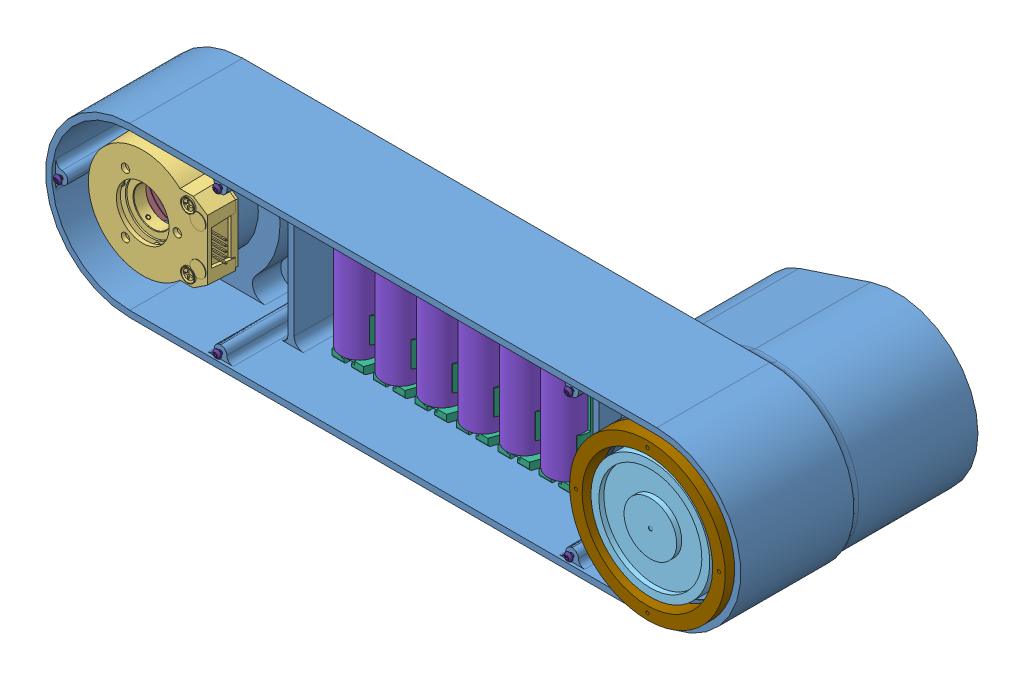
SolidWorks assembly Wall Link, configuration Default. Lengths in mm.
Overall size (351.79 85.09 127.22).
66 component instances, 23 part files, 117 mates.
Components (placement in the parent):
- Wall Link Frame-1: Wall Link Frame [Default] at (-125.008 20.7132 -31.1742) size (351.79 85.09 121.22)
- ring_gear-1: ring_gear [Default] at (-125.008 20.7132 -35.0242) x (0 0 -1) z (1 0 0) size (5 75 75)
- Magnet Encoders E3-X-750-X-H-D-X-1: Magnet Encoders E3-X-750-X-H-D-X [Default] at (141.692 20.7132 -54.2232) x (0 1 0) z (-1 0 0) size (55.98 16.26 66.52)
- magnet holder-1: magnet holder [Default] at (145.4704 22.0262 -2.1382) x (0.944598 0.32823 0) z (-0.32823 0.944598 0) size (50.8 63.9 50.6)
- EM237 Magnet-1: EM237 Magnet [Default] at (141.692 20.7132 10.3713) x (-0.997847 -0.065578 0) z (-0.065578 0.997847 0) size (60.08 25.02 60.08)
- PCB_Battery Assembly-3: PCB_Battery Assembly [Default] at (93.7956 -0.9181 88.7233) x (1 0 0) z (0 1 0) size (138.43 24.87 77.22)
  - Battery Holder - keystone-PN1043-1: Battery Holder - keystone-PN1043 [Default] at (-125.3925 103.3982 18.9155) x (1 0 0) z (0 0 -1) size (20.65 18.93 77.14)
  - Battery PCB-1: Battery PCB [Default] at (-148.3186 115.135 -16.9005) x (1 0 0) z (0 -1 0) size (138.43 77.06 1.59)
  - battery_6612-1: battery_6612 [Default] at (-117.0385 104.4035 -11.3639) x (-0.413992 0.91028 0) z (0.91028 0.413992 0) size (18.3 65.05 18.3)
  - battery_6612-2: battery_6612 [Default] at (-137.9935 104.4035 54.6265) x (-0.916106 0.400937 0) z (-0.400937 -0.916106 0) size (18.3 65.05 18.3)
  - Battery Holder - keystone-PN1043-2: Battery Holder - keystone-PN1043 [Default] at (-129.6396 103.3982 24.3471) x (-1 0 0) z (0 0 1) size (20.65 18.93 77.14)
  - Battery Holder - keystone-PN1043-3: Battery Holder - keystone-PN1043 [Default] at (-104.4375 103.3982 18.9155) x (1 0 0) z (0 0 -1) size (20.65 18.93 77.14)
  - battery_6612-3: battery_6612 [Default] at (-96.0835 104.4035 -10.3735) x (1 0 0) z (0 -1 0) size (18.3 65.05 18.3)
  - Battery Holder - keystone-PN1043-4: Battery Holder - keystone-PN1043 [Default] at (-83.4825 103.3982 18.9155) x (1 0 0) z (0 0 -1) size (20.65 18.93 77.14)
  - Battery Holder - keystone-PN1043-5: Battery Holder - keystone-PN1043 [Default] at (-45.8196 103.3982 24.3471) x (-1 0 0) z (0 0 1) size (20.65 18.93 77.14)
  - Battery Holder - keystone-PN1043-6: Battery Holder - keystone-PN1043 [Default] at (-41.5725 103.3982 18.9155) x (1 0 0) z (0 0 -1) size (20.65 18.93 77.14)
  - battery_6612-4: battery_6612 [Default] at (-75.1285 104.4035 -11.3639) x (-0.923728 -0.383049 0) z (-0.383049 0.923728 0) size (18.3 65.05 18.3)
  - battery_6612-5: battery_6612 [Default] at (-54.1735 104.4035 54.6265) x (-1 0 0) z (0 -1 0) size (18.3 65.05 18.3)
  - battery_6612-6: battery_6612 [Default] at (-33.2185 104.4035 -11.3639) x (-0.923728 -0.383049 0) z (-0.383049 0.923728 0) size (18.3 65.05 18.3)
- Delrin_Ring-1: Delrin_Ring [Default] at (141.692 20.7132 24.3883) x (1 0 0) z (0 1 0) size (78.74 9.53 78.74)
- Neoprene Ring-1: Neoprene Ring [Default] at (141.692 20.7132 14.8633) x (0 1 0) z (-1 0 0) size (78.74 3.17 78.74)
- Slip Ring M322M1-0600-1: Slip Ring M322M1-0600 [Default] at (141.692 20.7132 -74.8152) x (0.866025 0.5 0) z (0 0 1) size (44 44 48)
- Wall Link Acrylic Cover-1: Wall Link Acrylic Cover [Default] at (141.692 20.7132 18.0383) x (-1 0 0) z (0 1 0) size (280.8 1.59 78.74) (hidden)
- Magnet Encoders E3-X-750-X-H-D-X-2: Magnet Encoders E3-X-750-X-H-D-X [Default] at (-125.008 20.7132 0.8148) x (0 1 0) z (1 0 0) size (55.98 16.26 66.52)
- Acrylic Cover 2 Wall Link-1: Acrylic Cover 2 Wall Link [Default] at (141.692 20.7132 -101.5942) x (-1 0 0) z (0 0 1) size (103.7 76.2 1.59)
- Bearing - .750-1: Bearing - .750 [3760T241] at (-125.008 20.7132 -11.3454) x (-0.923728 -0.383049 0) z (0 0 -1) size (41.27 41.27 11.11)
- Bearing - .750-3: Bearing - .750 [3760T241] at (141.692 20.7132 -27.7755) size (41.27 41.27 11.11)
- Bearing - .750-2: Bearing - .750 [3760T241] at (141.692 20.7132 -38.888) x (0.923728 0.383049 0) z (0 0 -1) size (41.27 41.27 11.11)
- 1.625 Bore Internal Retaining Ring-1: 1.625 Bore Internal Retaining Ring [99142A560] at (-125.008 20.7132 -5.7892) x (-0.62577 0.780008 0) z (-0.780008 -0.62577 0) size (45.82 1.57 43.68)
- .75 Bore External Retaining Ring-1: .75 Bore External Retaining Ring [97633A250] at (141.692 21.2592 -44.9776) x (0 0 -1) z (1 0 0) size (1.07 23.39 21.18)
- 1.625 Bore Internal Retaining Ring-2: 1.625 Bore Internal Retaining Ring [99142A560] at (141.692 20.7132 -20.6444) x (1 0 0) z (0 -1 0) size (45.82 1.57 43.68)
- Dowel Pin - .0625-1: Dowel Pin - .0625 [97395A414] at (141.692 -15.4818 8.5133) x (0 0 1) z (0.923728 0.383049 0) size (19.05 1.59 1.59)
- Dowel Pin - .0625-2: Dowel Pin - .0625 [97395A414] at (141.692 56.9082 8.5133) x (0 0 1) z (0.923728 0.383049 0) size (19.05 1.59 1.59)
- Dowel Pin - .0625-3: Dowel Pin - .0625 [97395A414] at (177.887 20.7132 8.5133) x (0 0 1) z (0.923728 0.383049 0) size (19.05 1.59 1.59)
- Dowel Pin - .0625-4: Dowel Pin - .0625 [97395A414] at (105.497 20.7132 8.5133) x (0 0 1) z (0.923728 0.383049 0) size (19.05 1.59 1.59)
- 2-56 Screw-1: 2-56 Screw [98164A427] at (97.242 -15.4818 20.7942) size (4.17 4.17 10.95)
- 2-56 Screw-2: 2-56 Screw [98164A427] at (97.242 56.9082 20.7942) size (4.17 4.17 10.95)
- 2-56 Screw-3: 2-56 Screw [98164A427] at (-80.558 56.9082 20.7942) size (4.17 4.17 10.95)
- 2-56 Screw-4: 2-56 Screw [98164A427] at (-161.203 20.7132 20.7942) size (4.17 4.17 10.95)
- 2-56 Screw-5: 2-56 Screw [98164A427] at (-80.558 -15.4818 20.7942) size (4.17 4.17 10.95)
- M5 Screws-1: M5 Screws [91352A131] at (150.442 35.8687 -77.5652) x (-0.923728 -0.383049 0) z (0 0 -1) size (9.5 9.5 13.21)
- M5 Screws-2: M5 Screws [91352A131] at (150.442 5.5578 -77.5652) x (0.923728 0.383049 0) z (0 0 -1) size (9.5 9.5 13.21)
- M5 Screws-3: M5 Screws [91352A131] at (124.192 20.7132 -77.5652) x (-0.923728 -0.383049 0) z (0 0 -1) size (9.5 9.5 13.21)
- M5 Nylon Spacer-1: M5 Nylon Spacer [93657A042] at (150.442 35.8687 -69.4152) size (8 8 6)
- M5 Nylon Spacer-2: M5 Nylon Spacer [93657A042] at (124.192 20.7132 -69.4152) size (8 8 6)
- M5 Nylon Spacer-3: M5 Nylon Spacer [93657A042] at (150.442 5.5578 -69.4152) size (8 8 6)
- 4-40 Screws-1: 4-40 Screws [92949A108] at (-125.008 43.7256 2.3134) size (5.41 5.41 11.35)
- 4-40 Screws-2: 4-40 Screws [92949A108] at (141.692 -2.2992 -55.7218) x (0.923728 0.383049 0) z (0 0 -1) size (5.41 5.41 11.35)
- 4-40 Screws-3: 4-40 Screws [92949A108] at (141.692 43.7256 -55.7218) x (0.923728 0.383049 0) z (0 0 -1) size (5.41 5.41 11.35)
- 4-40 Screws-4: 4-40 Screws [92949A108] at (-125.008 -2.2992 2.3134) x (0.999053 -0.043504 0) z (0 0 1) size (5.41 5.41 11.35)
- 2-56 Screw-6: 2-56 Screw [98164A427] at (79.2674 20.7132 -102.7626) x (-0.923728 -0.383049 0) z (0 0 -1) size (4.17 4.17 10.95)
- 2-56 Screw-7: 2-56 Screw [98164A427] at (176.617 20.7132 -102.7626) x (-0.923728 -0.383049 0) z (0 0 -1) size (4.17 4.17 10.95)
- 2-56 Screw-8: 2-56 Screw [98164A427] at (116.292 49.0821 -102.7626) x (-0.923728 -0.383049 0) z (0 0 -1) size (4.17 4.17 10.95)
- 2-56 Screw-9: 2-56 Screw [98164A427] at (116.292 -7.6556 -102.7626) x (-0.923728 -0.383049 0) z (0 0 -1) size (4.17 4.17 10.95)
- 2-56 Screw-10: 2-56 Screw [98164A427] at (74.382 52.895 -23.6558) size (4.17 4.17 10.95)
- 2-56 Screw-12: 2-56 Screw [98164A427] at (74.382 -11.4686 -23.6558) size (4.17 4.17 10.95)
- 2-56 Screw-13: 2-56 Screw [98164A427] at (-57.698 52.895 -23.6558) size (4.17 4.17 10.95)
- 2-56 Screw-14: 2-56 Screw [98164A427] at (-57.698 -11.4686 -23.6558) size (4.17 4.17 10.95)
- #2 Spacer-1: #2 Spacer [94639A188] at (74.382 52.895 -28.793) x (0.8148 0.579742 0) z (0 0 1) size (6.35 6.35 4.76)
- #2 Spacer-2: #2 Spacer [94639A188] at (74.382 -11.4686 -28.793) x (0.211674 0.97734 0) z (0 0 1) size (6.35 6.35 4.76)
- #2 Spacer-3: #2 Spacer [94639A188] at (-57.698 52.895 -28.793) x (0.886571 -0.462592 0) z (0 0 1) size (6.35 6.35 4.76)
- #2 Spacer-4: #2 Spacer [94639A188] at (-57.698 -11.4686 -28.793) x (-0.923728 -0.383049 0) z (0 0 -1) size (6.35 6.35 4.76)
- 8-32 Low Profile Screws-1: 8-32 Low Profile Screws [92220A153] at (-125.008 -13.5768 -31.1742) x (0 0 1) z (-1 0 0) size (15.09 6.86 6.86)
- 8-32 Low Profile Screws-2: 8-32 Low Profile Screws [92220A153] at (-90.718 20.7132 -31.1742) x (0 0 1) z (-1 0 0) size (15.09 6.86 6.86)
- 8-32 Low Profile Screws-3: 8-32 Low Profile Screws [92220A153] at (-125.008 55.0032 -31.1742) x (0 0 1) z (-0.52487 0.851182 0) size (15.09 6.86 6.86)
- 8-32 Low Profile Screws-4: 8-32 Low Profile Screws [92220A153] at (-159.298 20.7132 -31.1742) x (0 0 1) z (-1 0 0) size (15.09 6.86 6.86)
Mates (geometry in assembly coordinates):
- Coincident1: coincident aligned: plane of Wall Link Frame-1 through (-125.008 20.7132 -37.5242) normal (0 0 -1); plane of ring_gear-1 through (-125.008 20.7132 -37.5242) normal (0 0 -1)
- Coincident2: coincident aligned: line of Wall Link Frame-1 through (-125.008 20.7132 -32.4442) axis (0 0 -1); line of ring_gear-1 through (-125.008 20.7132 -32.5242) axis (0 0 -1)
- Concentric1: concentric anti-aligned: cylinder of Magnet Encoders E3-X-750-X-H-D-X-1 through (141.692 20.7132 -60.7764) axis (0 0 -1) radius 9.5263; line of Wall Link Frame-1 through (141.692 20.7132 -50.7942) axis (0 0 1)
- Coincident4: coincident anti-aligned: plane of Wall Link Frame-1 through (-125.008 20.7132 -50.7942) normal (0 0 -1); plane of Magnet Encoders E3-X-750-X-H-D-X-1 through (141.692 20.7132 -50.7942) normal (0 0 1)
- Perpendicular1: perpendicular: line of Wall Link Frame-1 through (141.692 20.7132 -31.1742) axis (-1 0 0); line of Magnet Encoders E3-X-750-X-H-D-X-1 through (108.9495 36.0106 -66.4152) axis (0 -1 0)
- Coincident7: coincident aligned: line of Wall Link Frame-1 through (141.692 20.7132 -50.7942) axis (0 0 1); line of magnet holder-1 through (141.692 20.7132 -66.0342) axis (0 0 1)
- Coincident8: coincident aligned: plane of magnet holder-1; plane of EM237 Magnet-1 through (141.692 20.7132 -2.1382) normal (0 0 -1)
- Concentric2: concentric anti-aligned: line of Wall Link Frame-1 through (141.692 20.7132 -50.7942) axis (0 0 1); cylinder of EM237 Magnet-1 through (141.692 20.7132 22.8808) axis (0 0 -1) radius 30.0419
- Coincident12: coincident anti-aligned: plane of Wall Link Frame-1 through (-125.008 20.7132 -16.9017) normal (0 0 1); plane of Bearing - .750-1 through (-132.7004 39.2634 -16.9017) normal (0 0 -1)
- Coincident13: coincident anti-aligned: line of Wall Link Frame-1 through (-125.008 20.7132 -32.4442) axis (0 0 -1); line of Bearing - .750-1 through (-125.008 20.7132 -16.9017) axis (0 0 1)
- Coincident15: coincident anti-aligned: plane of Wall Link Frame-1 through (-125.008 20.7132 -5.7892) normal (0 0 1); plane of 1.625 Bore Internal Retaining Ring-1 through (-144.945 18.8067 -5.7892) normal (0 0 -1)
- Concentric3: concentric aligned: cylinder of Wall Link Frame-1 through (-125.008 20.7132 -4.062) axis (0 0 -1) radius 21.59; cylinder of 1.625 Bore Internal Retaining Ring-1 through (-125.008 20.7132 -4.2144) axis (0 0 -1) radius 22.9108
- Concentric4: concentric anti-aligned: line of Wall Link Frame-1 through (-125.008 20.7132 -32.4442) axis (0 0 -1); cylinder of Magnet Encoders E3-X-750-X-H-D-X-2 through (-125.008 20.7132 7.368) axis (0 0 1) radius 9.5263
- Coincident18: coincident anti-aligned: plane of Wall Link Frame-1 through (-125.008 20.7132 -2.6142) normal (0 0 1); plane of Magnet Encoders E3-X-750-X-H-D-X-2 through (-125.008 20.7132 -2.6142) normal (0 0 -1)
- Parallel1: parallel: line of Wall Link Frame-1 through (141.692 20.7132 -31.1742) axis (-1 0 0); plane of Magnet Encoders E3-X-750-X-H-D-X-2 through (-99.2764 41.2364 -0.76) normal (0 0.999391 0.034899)
- Concentric5: concentric aligned: line of Wall Link Frame-1 through (141.692 20.7132 19.6258) axis (0 0 -1); cylinder of Bearing - .750-2 through (141.692 20.7132 -44.4442) axis (0 0 -1) radius 20.6375
- Coincident20: coincident anti-aligned: plane of Wall Link Frame-1 through (141.692 20.7132 -44.4442) normal (0 0 1); plane of Bearing - .750-2 through (149.3843 2.1631 -44.4442) normal (0 0 -1)
- Concentric6: concentric anti-aligned: cylinder of Bearing - .750-3 through (141.692 20.7132 -22.2192) axis (0 0 1) radius 20.6375; line of Wall Link Frame-1 through (141.692 20.7132 19.6258) axis (0 0 -1)
- Coincident21: coincident anti-aligned: plane of Bearing - .750-2 through (149.3843 2.1631 -33.3317) normal (0 0 1); plane of Bearing - .750-3 through (141.692 40.7951 -33.3317) normal (0 0 -1)
- Coincident22: coincident anti-aligned: plane of Wall Link Frame-1 through (141.692 20.7132 -22.2192) normal (0 0 1); plane of 1.625 Bore Internal Retaining Ring-2 through (152.6808 3.9692 -22.2192) normal (0 0 -1)
- Concentric7: concentric anti-aligned: line of Wall Link Frame-1 through (141.692 20.7132 19.6258) axis (0 0 -1); cylinder of 1.625 Bore Internal Retaining Ring-2 through (141.692 20.7132 -22.2192) axis (0 0 1) radius 22.9108
- Coincident24: coincident anti-aligned: plane of magnet holder-1 through (153.6884 24.8818 -22.2192) normal (0 0 -1); plane of Bearing - .750-3 through (141.692 34.4687 -22.2192) normal (0 0 1)
- Coincident25: coincident anti-aligned: plane of magnet holder-1 through (141.692 20.7132 -44.4442) normal (0 0 -1); plane of .75 Bore External Retaining Ring-1 through (141.692 21.2592 -44.4442) normal (0 0 1)
- Concentric8: concentric anti-aligned: line of Wall Link Frame-1 through (141.692 20.7132 19.6258) axis (0 0 -1); cylinder of .75 Bore External Retaining Ring-1 through (141.692 20.7132 -45.511) axis (0 0 1) radius 10.592
- Concentric10: concentric anti-aligned: line of Wall Link Frame-1 through (141.692 20.7132 19.6258) axis (0 0 -1); cylinder of Neoprene Ring-1 through (141.692 20.7132 11.6883) axis (0 0 1) radius 33.02
- Concentric9: concentric aligned: cylinder of Wall Link Frame-1 through (105.497 20.7132 -1.0117) axis (0 0 1) radius 0.7937; cylinder of Neoprene Ring-1 through (105.497 20.7132 11.6883) axis (0 0 1) radius 0.7937
- Coincident27: coincident anti-aligned: plane of Wall Link Frame-1 through (141.692 20.7132 11.6883) normal (0 0 1); plane of Neoprene Ring-1 through (141.692 20.7132 11.6883) normal (0 0 -1)
- Coincident28: coincident anti-aligned: plane of Delrin_Ring-1 through (141.692 20.7132 14.8633) normal (0 0 -1); plane of Neoprene Ring-1 through (141.692 20.7132 14.8633) normal (0 0 1)
- Concentric11: concentric anti-aligned: line of Wall Link Frame-1 through (141.692 20.7132 19.6258) axis (0 0 -1); cylinder of Delrin_Ring-1 through (141.692 20.7132 14.8633) axis (0 0 1) radius 33.02
- Concentric12: concentric aligned: cylinder of Wall Link Frame-1 through (105.497 20.7132 -1.0117) axis (0 0 1) radius 0.7937; cylinder of Delrin_Ring-1 through (105.497 20.7132 14.8633) axis (0 0 1) radius 0.7937
- Concentric13: concentric aligned: cylinder of Wall Link Frame-1 through (105.497 20.7132 -1.0117) axis (0 0 1) radius 0.7937; cylinder of Dowel Pin - .0625-4 through (105.497 20.7132 -1.0117) axis (0 0 1) radius 0.7937
- Coincident30: coincident anti-aligned: plane of Wall Link Frame-1 through (105.497 20.7132 -1.0117) normal (0 0 1); plane of Dowel Pin - .0625-4 through (105.497 20.7132 -1.0117) normal (0 0 -1)
- Concentric15: concentric aligned: cylinder of Wall Link Frame-1 through (141.692 -15.4818 -1.0117) axis (0 0 1) radius 0.7937; cylinder of Dowel Pin - .0625-1 through (141.692 -15.4818 -1.0117) axis (0 0 1) radius 0.7937
- Coincident31: coincident anti-aligned: plane of Wall Link Frame-1 through (141.692 -15.4818 -1.0117) normal (0 0 1); plane of Dowel Pin - .0625-1 through (141.692 -15.4818 -1.0117) normal (0 0 -1)
- Concentric16: concentric aligned: cylinder of Wall Link Frame-1 through (177.887 20.7132 -1.0117) axis (0 0 1) radius 0.7937; cylinder of Dowel Pin - .0625-3 through (177.887 20.7132 -1.0117) axis (0 0 1) radius 0.7937
- Coincident32: coincident anti-aligned: plane of Wall Link Frame-1 through (177.887 20.7132 -1.0117) normal (0 0 1); plane of Dowel Pin - .0625-3 through (177.887 20.7132 -1.0117) normal (0 0 -1)
- Concentric17: concentric aligned: cylinder of Wall Link Frame-1 through (141.692 56.9082 -1.0117) axis (0 0 1) radius 0.7937; cylinder of Dowel Pin - .0625-2 through (141.692 56.9082 -1.0117) axis (0 0 1) radius 0.7937
- Coincident33: coincident anti-aligned: plane of Wall Link Frame-1 through (141.692 56.9082 -1.0117) normal (0 0 1); plane of Dowel Pin - .0625-2 through (141.692 56.9082 -1.0117) normal (0 0 -1)
- Concentric19: concentric aligned: line of Wall Link Frame-1 through (141.692 20.7132 19.6258) axis (0 0 -1); cylinder of Slip Ring M322M1-0600-1 through (141.692 20.7132 -58.4152) axis (0 0 -1) radius 3.8
- Distance1: distance = 6 mm anti-aligned: plane of Slip Ring M322M1-0600-1 through (160.7445 31.7132 -72.4152) normal (0 0 1); plane of Magnet Encoders E3-X-750-X-H-D-X-1 through (141.692 20.7132 -66.4152) normal (0 0 -1)
- Coincident34: coincident anti-aligned: plane of Wall Link Frame-1 through (-125.008 20.7132 18.0383) normal (0 0 1); plane of Wall Link Acrylic Cover-1 through (-125.008 20.7132 18.0383) normal (0 0 -1)
- Concentric20: concentric anti-aligned: cylinder of Wall Link Frame-1 through (-161.203 20.7132 18.0383) axis (0 0 1) radius 0.889; cylinder of Wall Link Acrylic Cover-1 through (-161.203 20.7132 19.6258) axis (0 0 -1) radius 1.0922
- Concentric21: concentric anti-aligned: cylinder of Wall Link Frame-1 through (-80.558 56.9082 18.0383) axis (0 0 1) radius 0.889; cylinder of Wall Link Acrylic Cover-1 through (-80.558 56.9082 19.6258) axis (0 0 -1) radius 1.0922
- Concentric22: concentric anti-aligned: cylinder of Wall Link Acrylic Cover-1 through (97.242 -15.4818 19.6258) axis (0 0 -1) radius 1.0922; line of 2-56 Screw-1 through (97.242 -15.4818 10.1008) axis (0 0 1)
- Coincident36: coincident anti-aligned: plane of Wall Link Acrylic Cover-1 through (-125.008 20.7132 19.6258) normal (0 0 1); plane of 2-56 Screw-1 through (97.242 -17.5646 19.6258) normal (0 0 -1)
- Concentric23: concentric anti-aligned: line of 2-56 Screw-2 through (97.242 56.9082 10.1008) axis (0 0 1); cylinder of Wall Link Acrylic Cover-1 through (97.242 56.9082 19.6258) axis (0 0 -1) radius 1.0922
- Coincident37: coincident anti-aligned: plane of Wall Link Acrylic Cover-1 through (-125.008 20.7132 19.6258) normal (0 0 1); plane of 2-56 Screw-2 through (97.242 54.8254 19.6258) normal (0 0 -1)
- Concentric24: concentric anti-aligned: cylinder of Wall Link Acrylic Cover-1 through (-80.558 56.9082 19.6258) axis (0 0 -1) radius 1.0922; line of 2-56 Screw-3 through (-80.558 56.9082 10.1008) axis (0 0 1)
- Coincident39: coincident anti-aligned: plane of Wall Link Acrylic Cover-1 through (-125.008 20.7132 19.6258) normal (0 0 1); plane of 2-56 Screw-3 through (-80.558 54.8254 19.6258) normal (0 0 -1)
- Concentric25: concentric anti-aligned: cylinder of Wall Link Acrylic Cover-1 through (-80.558 -15.4818 19.6258) axis (0 0 -1) radius 1.0922; line of 2-56 Screw-5 through (-80.558 -15.4818 10.1008) axis (0 0 1)
- Coincident41: coincident anti-aligned: plane of Wall Link Acrylic Cover-1 through (-125.008 20.7132 19.6258) normal (0 0 1); plane of 2-56 Screw-5 through (-80.558 -17.5646 19.6258) normal (0 0 -1)
- Concentric26: concentric anti-aligned: cylinder of Wall Link Acrylic Cover-1 through (-161.203 20.7132 19.6258) axis (0 0 -1) radius 1.0922; line of 2-56 Screw-4 through (-161.203 20.7132 10.1008) axis (0 0 1)
- Coincident43: coincident anti-aligned: plane of Wall Link Acrylic Cover-1 through (-125.008 20.7132 19.6258) normal (0 0 1); plane of 2-56 Screw-4 through (-161.203 18.6304 19.6258) normal (0 0 -1)
- Concentric27: concentric aligned: cylinder of Magnet Encoders E3-X-750-X-H-D-X-1 through (124.192 20.7132 -66.4152) axis (0 0 -1) radius 2.1; cylinder of Slip Ring M322M1-0600-1 through (124.192 20.7132 -74.8152) axis (0 0 -1) radius 2.75
- Concentric29: concentric aligned: cylinder of Magnet Encoders E3-X-750-X-H-D-X-1 through (150.442 5.5578 -66.4152) axis (0 0 -1) radius 2.1; cylinder of Slip Ring M322M1-0600-1 through (150.442 5.5578 -74.8152) axis (0 0 -1) radius 2.75
- Concentric30: concentric aligned: cylinder of Magnet Encoders E3-X-750-X-H-D-X-1 through (150.442 35.8687 -66.4152) axis (0 0 -1) radius 2.1; cylinder of Slip Ring M322M1-0600-1 through (150.442 35.8687 -74.8152) axis (0 0 -1) radius 2.75
- Concentric31: concentric aligned: cylinder of Slip Ring M322M1-0600-1 through (124.192 20.7132 -74.8152) axis (0 0 -1) radius 2.75; line of M5 Screws-3 through (124.192 20.7132 -64.8152) axis (0 0 -1)
- Coincident45: coincident anti-aligned: plane of Slip Ring M322M1-0600-1 through (141.692 20.7132 -74.8152) normal (0 0 -1); plane of M5 Screws-3 through (126.0114 16.3255 -74.8152) normal (0 0 1)
- Concentric32: concentric aligned: cylinder of Slip Ring M322M1-0600-1 through (150.442 35.8687 -74.8152) axis (0 0 -1) radius 2.75; line of M5 Screws-1 through (150.442 35.8687 -64.8152) axis (0 0 -1)
- Coincident47: coincident anti-aligned: plane of Slip Ring M322M1-0600-1 through (141.692 20.7132 -74.8152) normal (0 0 -1); plane of M5 Screws-1 through (152.2614 31.481 -74.8152) normal (0 0 1)
- Concentric33: concentric aligned: cylinder of Slip Ring M322M1-0600-1 through (150.442 5.5578 -74.8152) axis (0 0 -1) radius 2.75; line of M5 Screws-2 through (150.442 5.5578 -64.8152) axis (0 0 -1)
- Coincident49: coincident anti-aligned: plane of Slip Ring M322M1-0600-1 through (141.692 20.7132 -74.8152) normal (0 0 -1); plane of M5 Screws-2 through (148.6225 9.9455 -74.8152) normal (0 0 1)
- Concentric34: concentric aligned: cylinder of Slip Ring M322M1-0600-1 through (124.192 20.7132 -74.8152) axis (0 0 -1) radius 2.75; cylinder of M5 Nylon Spacer-2 through (124.192 20.7132 -66.4152) axis (0 0 -1) radius 2.65
- Coincident50: coincident anti-aligned: plane of Magnet Encoders E3-X-750-X-H-D-X-1 through (141.692 20.7132 -66.4152) normal (0 0 -1); plane of M5 Nylon Spacer-2 through (124.192 20.7132 -66.4152) normal (0 0 1)
- Coincident51: coincident anti-aligned: plane of Magnet Encoders E3-X-750-X-H-D-X-1 through (141.692 20.7132 -66.4152) normal (0 0 -1); plane of M5 Nylon Spacer-1 through (150.442 35.8687 -66.4152) normal (0 0 1)
- Concentric35: concentric aligned: cylinder of Slip Ring M322M1-0600-1 through (150.442 35.8687 -74.8152) axis (0 0 -1) radius 2.75; cylinder of M5 Nylon Spacer-1 through (150.442 35.8687 -66.4152) axis (0 0 -1) radius 2.65
- Concentric36: concentric aligned: cylinder of Slip Ring M322M1-0600-1 through (150.442 5.5578 -74.8152) axis (0 0 -1) radius 2.75; cylinder of M5 Nylon Spacer-3 through (150.442 5.5578 -66.4152) axis (0 0 -1) radius 2.65
- Coincident52: coincident anti-aligned: plane of Magnet Encoders E3-X-750-X-H-D-X-1 through (141.692 20.7132 -66.4152) normal (0 0 -1); plane of M5 Nylon Spacer-3 through (150.442 5.5578 -66.4152) normal (0 0 1)
- Concentric37: concentric aligned: cylinder of Wall Link Frame-1 through (-90.718 20.7132 -32.4442) axis (0 0 -1) radius 1.7272; cylinder of ring_gear-1 through (-90.718 20.7132 -32.5242) axis (0 0 -1) radius 2.1526
- Concentric42: concentric anti-aligned: cylinder of Magnet Encoders E3-X-750-X-H-D-X-2 through (-125.008 43.7256 0.8148) axis (0 0 -1) radius 1.4351; line of 4-40 Screws-1 through (-125.008 43.7256 -8.7102) axis (0 0 1)
- Coincident62: coincident anti-aligned: plane of Magnet Encoders E3-X-750-X-H-D-X-2 through (-125.008 20.7132 0.8148) normal (0 0 1); plane of 4-40 Screws-1 through (-125.008 41.0205 0.8148) normal (0 0 -1)
- Concentric43: concentric anti-aligned: cylinder of Magnet Encoders E3-X-750-X-H-D-X-2 through (-125.008 -2.2992 0.8148) axis (0 0 -1) radius 1.4351; line of 4-40 Screws-4 through (-125.008 -2.2992 -8.7102) axis (0 0 1)
- Coincident64: coincident anti-aligned: plane of Magnet Encoders E3-X-750-X-H-D-X-2 through (-125.008 20.7132 0.8148) normal (0 0 1); plane of 4-40 Screws-4 through (-125.1257 -5.0017 0.8148) normal (0 0 -1)
- Concentric44: concentric anti-aligned: cylinder of Magnet Encoders E3-X-750-X-H-D-X-1 through (141.692 43.7256 -54.2232) axis (0 0 1) radius 1.4351; line of 4-40 Screws-3 through (141.692 43.7256 -44.6982) axis (0 0 -1)
- Coincident66: coincident anti-aligned: plane of Magnet Encoders E3-X-750-X-H-D-X-1 through (141.692 20.7132 -54.2232) normal (0 0 -1); plane of 4-40 Screws-3 through (140.6558 46.2244 -54.2232) normal (0 0 1)
- Concentric45: concentric anti-aligned: cylinder of Magnet Encoders E3-X-750-X-H-D-X-1 through (141.692 -2.2992 -54.2232) axis (0 0 1) radius 1.4351; line of 4-40 Screws-2 through (141.692 -2.2992 -44.6982) axis (0 0 -1)
- Coincident68: coincident anti-aligned: plane of Magnet Encoders E3-X-750-X-H-D-X-1 through (141.692 20.7132 -54.2232) normal (0 0 -1); plane of 4-40 Screws-2 through (140.6558 0.1996 -54.2232) normal (0 0 1)
- Coincident69: coincident anti-aligned: plane of Wall Link Frame-1 through (-125.008 20.7132 -100.0067) normal (0 0 -1); plane of Acrylic Cover 2 Wall Link-1 through (141.692 20.7132 -100.0067) normal (0 0 1)
- Concentric46: concentric aligned: cylinder of Wall Link Frame-1 through (176.617 20.7132 -100.0067) axis (0 0 -1) radius 0.889; cylinder of Acrylic Cover 2 Wall Link-1 through (176.617 20.7132 -100.0067) axis (0 0 -1) radius 1.0922
- Concentric47: concentric aligned: cylinder of Wall Link Frame-1 through (79.2674 20.7132 -100.0067) axis (0 0 -1) radius 0.889; cylinder of Acrylic Cover 2 Wall Link-1 through (79.2674 20.7132 -100.0067) axis (0 0 -1) radius 1.0922
- Concentric48: concentric aligned: cylinder of Wall Link Frame-1 through (116.292 49.0821 -100.0067) axis (0 0 -1) radius 0.889; cylinder of Acrylic Cover 2 Wall Link-1 through (116.292 49.0821 -100.0067) axis (0 0 -1) radius 1.0922
- Concentric49: concentric aligned: cylinder of Wall Link Frame-1 through (116.292 -7.6556 -100.0067) axis (0 0 -1) radius 0.889; cylinder of Acrylic Cover 2 Wall Link-1 through (116.292 -7.6556 -100.0067) axis (0 0 -1) radius 1.0922
- Coincident70: coincident anti-aligned: plane of Acrylic Cover 2 Wall Link-1 through (141.692 20.7132 -101.5942) normal (0 0 -1); plane of 2-56 Screw-7 through (177.4148 18.7893 -101.5942) normal (0 0 1)
- Concentric51: concentric aligned: cylinder of Acrylic Cover 2 Wall Link-1 through (176.617 20.7132 -100.0067) axis (0 0 -1) radius 1.0922; cylinder of 2-56 Screw-7 through (176.617 20.7132 -102.7626) axis (0 0 -1) radius 2.0828
- Coincident71: coincident anti-aligned: plane of Acrylic Cover 2 Wall Link-1 through (141.692 20.7132 -101.5942) normal (0 0 -1); plane of 2-56 Screw-9 through (117.0898 -9.5795 -101.5942) normal (0 0 1)
- Concentric52: concentric aligned: cylinder of Acrylic Cover 2 Wall Link-1 through (116.292 -7.6556 -100.0067) axis (0 0 -1) radius 1.0922; cylinder of 2-56 Screw-9 through (116.292 -7.6556 -102.7626) axis (0 0 -1) radius 2.0828
- Coincident72: coincident anti-aligned: plane of Acrylic Cover 2 Wall Link-1 through (141.692 20.7132 -101.5942) normal (0 0 -1); plane of 2-56 Screw-8 through (117.0898 47.1581 -101.5942) normal (0 0 1)
- Concentric53: concentric aligned: cylinder of Acrylic Cover 2 Wall Link-1 through (116.292 49.0821 -100.0067) axis (0 0 -1) radius 1.0922; cylinder of 2-56 Screw-8 through (116.292 49.0821 -102.7626) axis (0 0 -1) radius 2.0828
- Coincident73: coincident anti-aligned: plane of Acrylic Cover 2 Wall Link-1 through (141.692 20.7132 -101.5942) normal (0 0 -1); plane of 2-56 Screw-6 through (80.0652 18.7893 -101.5942) normal (0 0 1)
- Concentric54: concentric aligned: cylinder of Acrylic Cover 2 Wall Link-1 through (79.2674 20.7132 -100.0067) axis (0 0 -1) radius 1.0922; cylinder of 2-56 Screw-6 through (79.2674 20.7132 -102.7626) axis (0 0 -1) radius 2.0828
- Concentric55: concentric anti-aligned: cylinder of PCB_Battery Assembly-3/Battery PCB-1 through (74.382 52.895 -24.8242) axis (0 0 -1) radius 1.0922; cylinder of 2-56 Screw-10 through (74.382 52.895 -23.6558) axis (0 0 1) radius 2.0828
- Coincident74: coincident anti-aligned: plane of PCB_Battery Assembly-3/Battery PCB-1 through (-54.523 -17.8186 -24.8242) normal (0 0 1); plane of 2-56 Screw-10 through (74.382 50.8122 -24.8242) normal (0 0 -1)
- Concentric56: concentric anti-aligned: cylinder of PCB_Battery Assembly-3/Battery PCB-1 through (74.382 -11.4686 -24.8242) axis (0 0 -1) radius 1.0922; cylinder of 2-56 Screw-12 through (74.382 -11.4686 -23.6558) axis (0 0 1) radius 2.0828
- Coincident75: coincident anti-aligned: plane of PCB_Battery Assembly-3/Battery PCB-1 through (-54.523 -17.8186 -24.8242) normal (0 0 1); plane of 2-56 Screw-12 through (74.382 -13.5514 -24.8242) normal (0 0 -1)
- Concentric57: concentric anti-aligned: cylinder of PCB_Battery Assembly-3/Battery PCB-1 through (-57.698 52.895 -24.8242) axis (0 0 -1) radius 1.0922; cylinder of 2-56 Screw-13 through (-57.698 52.895 -23.6558) axis (0 0 1) radius 2.0828
- Coincident76: coincident anti-aligned: plane of PCB_Battery Assembly-3/Battery PCB-1 through (-54.523 -17.8186 -24.8242) normal (0 0 1); plane of 2-56 Screw-13 through (-57.698 50.8122 -24.8242) normal (0 0 -1)
- Concentric58: concentric anti-aligned: cylinder of PCB_Battery Assembly-3/Battery PCB-1 through (-57.698 -11.4686 -24.8242) axis (0 0 -1) radius 1.0922; cylinder of 2-56 Screw-14 through (-57.698 -11.4686 -23.6558) axis (0 0 1) radius 2.0828
- Coincident77: coincident anti-aligned: plane of PCB_Battery Assembly-3/Battery PCB-1 through (-54.523 -17.8186 -24.8242) normal (0 0 1); plane of 2-56 Screw-14 through (-57.698 -13.5514 -24.8242) normal (0 0 -1)
- Concentric59: concentric anti-aligned: cylinder of Wall Link Frame-1 through (74.382 52.895 -31.1742) axis (0 0 1) radius 0.889; cylinder of #2 Spacer-1 through (74.382 52.895 -26.4117) axis (0 0 -1) radius 3.175
- Coincident78: coincident anti-aligned: plane of Wall Link Frame-1 through (-125.008 20.7132 -31.1742) normal (0 0 1); plane of #2 Spacer-1 through (74.382 52.895 -31.1742) normal (0 0 -1)
- Concentric60: concentric anti-aligned: cylinder of Wall Link Frame-1 through (74.382 -11.4686 -31.1742) axis (0 0 1) radius 0.889; cylinder of #2 Spacer-2 through (74.382 -11.4686 -26.4117) axis (0 0 -1) radius 1.143
- Coincident79: coincident anti-aligned: plane of Wall Link Frame-1 through (-125.008 20.7132 -31.1742) normal (0 0 1); plane of #2 Spacer-2 through (74.382 -11.4686 -31.1742) normal (0 0 -1)
- Concentric61: concentric anti-aligned: cylinder of Wall Link Frame-1 through (-57.698 52.895 -31.1742) axis (0 0 1) radius 0.889; cylinder of #2 Spacer-3 through (-57.698 52.895 -26.4117) axis (0 0 -1) radius 1.143
- Coincident80: coincident anti-aligned: plane of Wall Link Frame-1 through (-125.008 20.7132 -31.1742) normal (0 0 1); plane of #2 Spacer-3 through (-57.698 52.895 -31.1742) normal (0 0 -1)
- Coincident81: coincident anti-aligned: plane of Wall Link Frame-1 through (-125.008 20.7132 -31.1742) normal (0 0 1); plane of #2 Spacer-4 through (-57.698 -11.4686 -31.1742) normal (0 0 -1)
- Concentric62: concentric aligned: cylinder of #2 Spacer-4 through (-57.698 -11.4686 -31.1742) axis (0 0 1) radius 1.143; cylinder of Wall Link Frame-1 through (-57.698 -11.4686 -31.1742) axis (0 0 1) radius 0.889
- Coincident82: coincident anti-aligned: plane of PCB_Battery Assembly-3/Battery PCB-1 through (-54.523 -17.8186 -26.4117) normal (0 0 -1); plane of #2 Spacer-3 through (-57.698 52.895 -26.4117) normal (0 0 1)
- Concentric63: concentric aligned: cylinder of PCB_Battery Assembly-3/Battery PCB-1 through (-57.698 52.895 -24.8242) axis (0 0 -1) radius 1.0922; cylinder of #2 Spacer-3 through (-57.698 52.895 -26.4117) axis (0 0 -1) radius 1.143
- Concentric64: concentric anti-aligned: cylinder of PCB_Battery Assembly-3/Battery PCB-1 through (-57.698 -11.4686 -24.8242) axis (0 0 -1) radius 1.0922; cylinder of #2 Spacer-4 through (-57.698 -11.4686 -31.1742) axis (0 0 1) radius 1.143
- Concentric65: concentric anti-aligned: cylinder of ring_gear-1 through (-125.008 -13.5768 -32.5242) axis (0 0 -1) radius 2.1526; cylinder of 8-32 Low Profile Screws-1 through (-125.008 -13.5768 -37.5242) axis (0 0 1) radius 3.429
- Coincident83: coincident anti-aligned: plane of ring_gear-1 through (-125.008 20.7132 -37.5242) normal (0 0 -1); plane of 8-32 Low Profile Screws-1 through (-125.008 -10.1478 -37.5242) normal (0 0 1)
- Concentric66: concentric anti-aligned: cylinder of ring_gear-1 through (-159.298 20.7132 -32.5242) axis (0 0 -1) radius 2.1526; cylinder of 8-32 Low Profile Screws-4 through (-159.298 20.7132 -37.5242) axis (0 0 1) radius 3.429
- Coincident84: coincident anti-aligned: plane of ring_gear-1 through (-125.008 20.7132 -37.5242) normal (0 0 -1); plane of 8-32 Low Profile Screws-4 through (-159.298 24.1422 -37.5242) normal (0 0 1)
- Concentric67: concentric anti-aligned: cylinder of ring_gear-1 through (-125.008 55.0032 -32.5242) axis (0 0 -1) radius 2.1526; cylinder of 8-32 Low Profile Screws-3 through (-125.008 55.0032 -37.5242) axis (0 0 1) radius 3.429
- Coincident85: coincident anti-aligned: plane of ring_gear-1 through (-125.008 20.7132 -37.5242) normal (0 0 -1); plane of 8-32 Low Profile Screws-3 through (-122.0893 56.803 -37.5242) normal (0 0 1)
- Concentric68: concentric anti-aligned: cylinder of ring_gear-1 through (-90.718 20.7132 -32.5242) axis (0 0 -1) radius 2.1526; cylinder of 8-32 Low Profile Screws-2 through (-90.718 20.7132 -37.5242) axis (0 0 1) radius 3.429
- Coincident86: coincident anti-aligned: plane of ring_gear-1 through (-125.008 20.7132 -37.5242) normal (0 0 -1); plane of 8-32 Low Profile Screws-2 through (-90.718 24.1422 -37.5242) normal (0 0 1)
